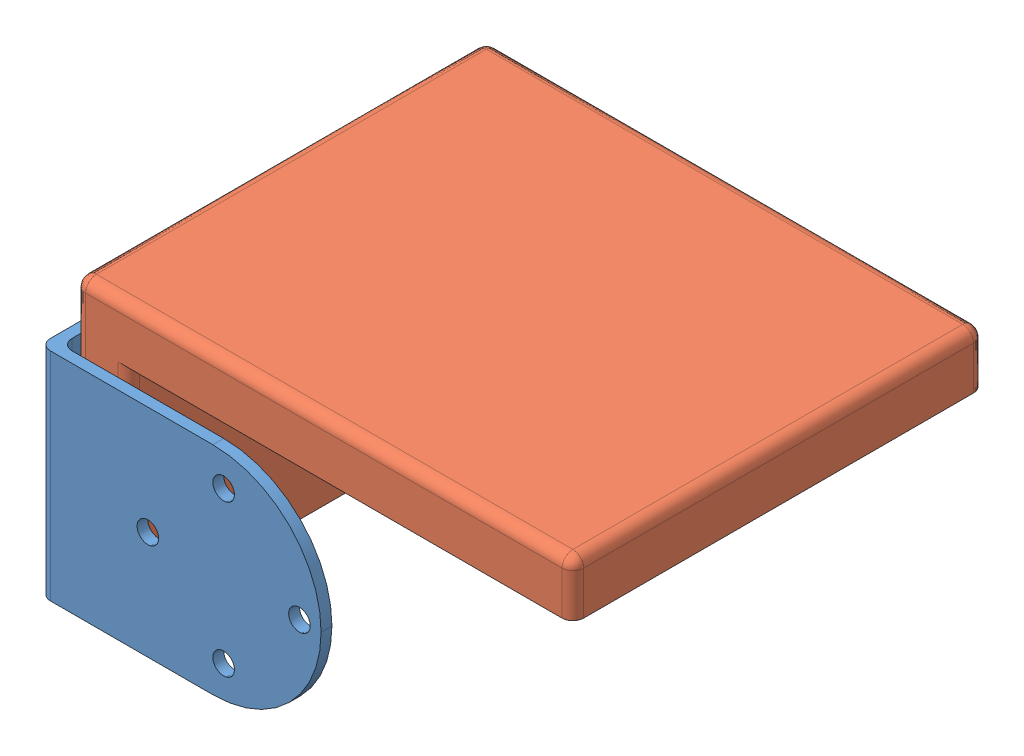
SolidWorks assembly moteur-complet, configuration Défaut. Lengths in mm.
Overall size (49 25.5 42.5).
11 component instances, 5 part files, 27 mates.
Components (placement in the parent):
- moteur-1: moteur [Défaut] at (-9.5825 -1.0731 48.8) size (45.5 20 48.8) (hidden)
- moteur-support-fixe-1: moteur-support-fixe [Défaut] at (-5.7196 9.1116 16.94) x (1 0 0) z (0 -1 0) size (26.58 42.5 20)
- moteur_semelle-1: moteur_semelle [Défaut] at (-31.3007 -10.8884 28.55) x (-1 0 0) z (0 0 1) size (47 25 38)
- ecrou-h-m2-1: ecrou-h-m2 [6007 HU M2] at (-27.7007 -8.3884 21.05) x (0 0.5 -0.866025) z (0 -0.866025 -0.5) size (4 1.6 4.62)
- ecrou-h-m2-2: ecrou-h-m2 [6007 HU M2] at (-27.7007 -8.3884 36.05) x (0 -0.5 -0.866025) z (0 -0.866025 0.5) size (4 1.6 4.62)
- ecrou-h-m2-3: ecrou-h-m2 [6007 HU M2] at (-27.7007 6.6116 36.05) x (0 -0.5 -0.866025) z (0 -0.866025 0.5) size (4 1.6 4.62)
- ecrou-h-m2-4: ecrou-h-m2 [6007 HU M2] at (-27.7007 6.6116 21.05) x (0 -1 0) z (0 0 1) size (4 1.6 4.62)
- vis-chc-m2x5-1: vis-chc-m2x5 [Vis CHC M2x5] at (-32.3007 -8.3884 36.05) x (0 -0.454411 0.890792) z (0 -0.890792 -0.454411) size (3.8 7 3.8)
- vis-chc-m2x5-2: vis-chc-m2x5 [Vis CHC M2x5] at (-32.3007 6.6116 36.05) x (0 -0.381849 0.924225) z (0 -0.924225 -0.381849) size (3.8 7 3.8)
- vis-chc-m2x5-3: vis-chc-m2x5 [Vis CHC M2x5] at (-32.3007 6.6116 21.05) x (0 -0.381849 0.924225) z (0 -0.924225 -0.381849) size (3.8 7 3.8)
- vis-chc-m2x5-4: vis-chc-m2x5 [Vis CHC M2x5] at (-32.3007 -8.3884 21.05) x (0 -0.381849 0.924225) z (0 -0.924225 -0.381849) size (3.8 7 3.8)
Mates (geometry in assembly coordinates):
- Coaxiale12: concentric aligned: cylinder of moteur-1 through (-22.3007 -0.8884 43.8) axis (0 0 1) radius 0.79; cylinder of support_fixe-1 through (-22.3007 -0.8884 7.299) axis (0 0 1) radius 1
- Coaxiale13: concentric aligned: cylinder of moteur-1 through (-15.3007 -7.8884 43.8) axis (0 0 1) radius 0.79; cylinder of support_fixe-1 through (-15.3007 -7.8884 7.299) axis (0 0 1) radius 1
- Coïncidente2: coincident anti-aligned: plane of moteur-1 through (-9.5825 -1.0731 48.8) normal (0 0 1); plane of support_fixe-1 through (-30.3007 -10.8884 48.8) normal (0 0 -1)
- Coïncidente3: coincident anti-aligned: plane of moteur-support-fixe-1 through (-31.3007 -10.8884 9.3) normal (1 0 0); plane of moteur_semelle-1 through (-31.3007 14.1116 9.55) normal (-1 0 0)
- Coïncidente5: coincident anti-aligned: plane of moteur-1 through (-25.3007 9.1116 8.3) normal (0 1 0); plane of moteur_semelle-1 through (14.6993 9.1116 47.55) normal (0 -1 0)
- Distance1: distance = 0.2 mm: line of moteur-support-fixe-1 through (-30.3007 -10.8884 48.8) axis (1 0 0); line of moteur_semelle-1 through (-26.3007 -10.8884 48.6) axis (-1 0 0)
- Coaxiale14: concentric anti-aligned: cylinder of moteur-support-fixe-1 through (-5.7186 -0.8884 28.55) axis (-1 0 0) radius 4; cylinder of moteur_semelle-1 through (-32.3007 -0.8884 28.55) axis (1 0 0) radius 4
- Coaxiale15: concentric anti-aligned: cylinder of moteur_semelle-1 through (14.7003 -8.3884 21.05) axis (-1 0 0) radius 1; cylinder of ecrou-h-m2-1 through (-29.3007 -8.3884 21.05) axis (1 0 0) radius 0.7835
- Parallèle2: parallel anti-aligned: plane of moteur_semelle-1 through (-29.3007 -10.4063 22.215) normal (0 1 0); plane of ecrou-h-m2-1 through (-29.3007 -10.3884 22.2047) normal (0 -1 0)
- Coïncidente9: coincident anti-aligned: plane of moteur_semelle-1 through (-29.3007 -10.8884 28.55) normal (1 0 0); plane of ecrou-h-m2-1 through (-29.3007 -6.3884 19.8953) normal (-1 0 0)
- Coaxiale16: concentric anti-aligned: cylinder of moteur_semelle-1 through (14.7003 6.6116 36.05) axis (-1 0 0) radius 1; cylinder of ecrou-h-m2-3 through (-29.3007 6.6116 36.05) axis (1 0 0) radius 0.7835
- Coaxiale17: concentric anti-aligned: cylinder of moteur_semelle-1 through (14.7003 6.6116 21.05) axis (-1 0 0) radius 1; cylinder of ecrou-h-m2-4 through (-29.3007 6.6116 21.05) axis (1 0 0) radius 0.7835
- Coaxiale18: concentric anti-aligned: cylinder of moteur_semelle-1 through (14.7003 -8.3884 36.05) axis (-1 0 0) radius 1; cylinder of ecrou-h-m2-2 through (-29.3007 -8.3884 36.05) axis (1 0 0) radius 0.7835
- Parallèle3: parallel anti-aligned: plane of moteur_semelle-1 through (-29.3007 -10.4063 37.215) normal (0 1 0); plane of ecrou-h-m2-2 through (-29.3007 -10.3884 37.2047) normal (0 -1 0)
- Coïncidente11: coincident anti-aligned: plane of moteur_semelle-1 through (-29.3007 -10.8884 28.55) normal (1 0 0); plane of ecrou-h-m2-2 through (-29.3007 -8.3884 33.7406) normal (-1 0 0)
- Parallèle4: parallel anti-aligned: plane of moteur_semelle-1 through (-29.3007 4.5937 22.215) normal (0 1 0); plane of ecrou-h-m2-4 through (-29.3007 4.6116 22.2047) normal (0 -1 0)
- Coïncidente13: coincident anti-aligned: plane of moteur_semelle-1 through (-29.3007 -10.8884 28.55) normal (1 0 0); plane of ecrou-h-m2-4 through (-29.3007 4.6116 19.8953) normal (-1 0 0)
- Parallèle5: parallel anti-aligned: plane of moteur_semelle-1 through (-29.3007 4.5937 37.215) normal (0 1 0); plane of ecrou-h-m2-3 through (-29.3007 4.6116 37.2047) normal (0 -1 0)
- Coïncidente15: coincident anti-aligned: plane of moteur_semelle-1 through (-29.3007 -10.8884 28.55) normal (1 0 0); plane of ecrou-h-m2-3 through (-29.3007 6.6116 33.7406) normal (-1 0 0)
- Coaxiale20: concentric: cylinder of moteur-support-fixe-1 through (-5.7186 -8.3884 36.05) axis (-1 0 0) radius 1; cylinder of vis-chc-m2x5-1 through (-30.5256 -8.3884 36.05) axis (-1 0 0) radius 1
- Coaxiale21: concentric: cylinder of moteur-support-fixe-1 through (-5.7186 -8.3884 21.05) axis (-1 0 0) radius 1; cylinder of vis-chc-m2x5-4 through (-32.3061 -8.3884 21.05) axis (-1 0 0) radius 1
- Coaxiale22: concentric: cylinder of moteur-support-fixe-1 through (-5.7186 6.6116 21.05) axis (-1 0 0) radius 1; cylinder of vis-chc-m2x5-3 through (-27.3007 6.6116 21.05) axis (-1 0 0) radius 1
- Coaxiale23: concentric: cylinder of moteur-support-fixe-1 through (-5.7186 6.6116 36.05) axis (-1 0 0) radius 1; cylinder of vis-chc-m2x5-2 through (-27.3007 6.6116 36.05) axis (-1 0 0) radius 1
- Coïncidente18: coincident anti-aligned: plane of moteur-support-fixe-1 through (-32.3007 -10.8884 48.8) normal (-1 0 0); plane of vis-chc-m2x5-2 through (-32.3007 6.6116 36.05) normal (1 0 0)
- Coïncidente19: coincident anti-aligned: plane of moteur-support-fixe-1 through (-32.3007 -10.8884 48.8) normal (-1 0 0); plane of vis-chc-m2x5-3 through (-32.3007 6.6116 21.05) normal (1 0 0)
- Coïncidente20: coincident anti-aligned: plane of moteur-support-fixe-1 through (-32.3007 -10.8884 48.8) normal (-1 0 0); plane of vis-chc-m2x5-1 through (-32.3007 -8.3884 36.05) normal (1 0 0)
- Coïncidente21: coincident anti-aligned: plane of moteur-support-fixe-1 through (-32.3007 -10.8884 48.8) normal (-1 0 0); plane of vis-chc-m2x5-4 through (-32.3007 -8.3884 21.05) normal (1 0 0)
